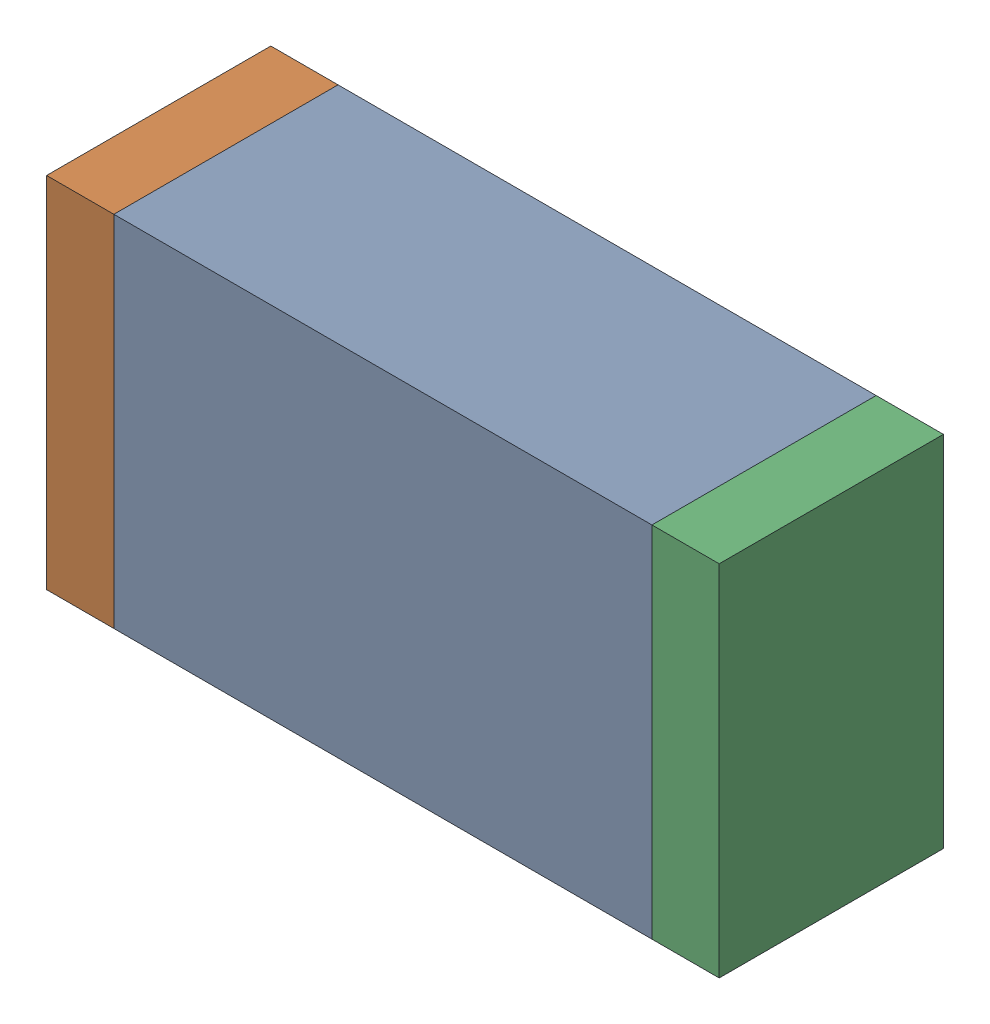
SolidWorks assembly D8, configuration Default. Lengths in mm.
Overall size (1.5 0.8 0.5).
6 component instances, 2 part files, 0 mates.
Components (placement in the parent):
- 836752368-1: 836752368 [Default] at (111.15 15.55 0) size (1.2 0.8 0.5)
  - Extruded-1: Extruded [Default] at origin size (1.2 0.8 0.5)
- 836752496-1: 836752496 [Default] at (110.475 15.55 0) size (0.15 0.8 0.5)
  - Extruded_2-1: Extruded_2 [Default] at origin size (0.15 0.8 0.5)
- 836752496-2: 836752496 [Default] at (111.825 15.55 0) size (0.15 0.8 0.5)
  - Extruded_2-1: Extruded_2 [Default] at origin size (0.15 0.8 0.5)
